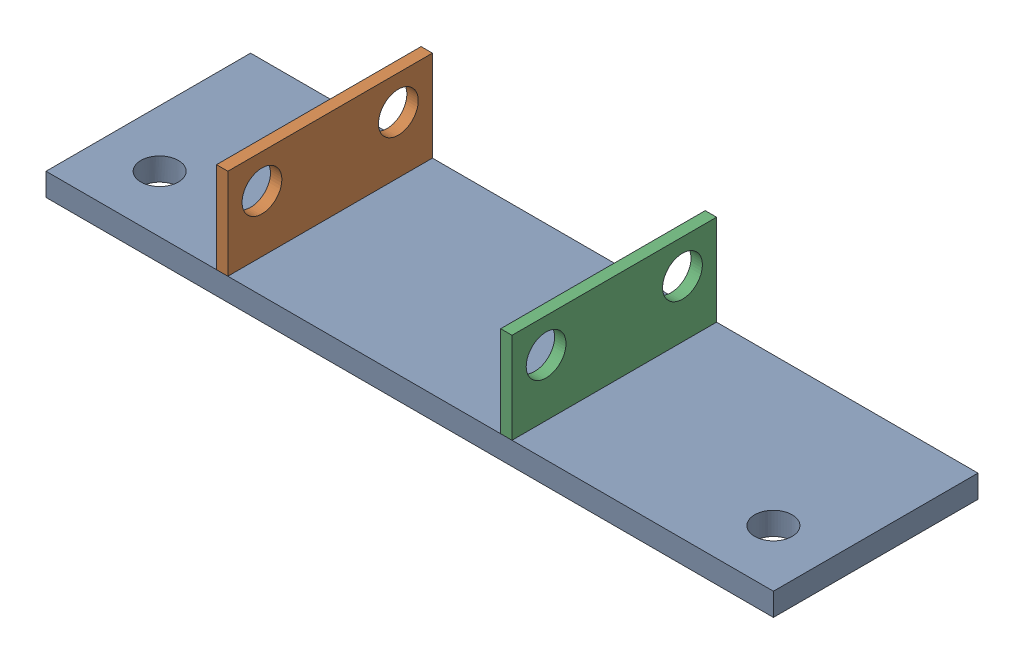
SolidWorks assembly Cam_Support_Ass_3, configuration Default. Lengths in mm.
Overall size (406.4 63.5 114.3).
3 component instances, 2 part files, 0 mates.
Components (placement in the parent):
- 01-020-00-0-1: 01-020-00-0 [Default] at (-198.1826 -10.9875 112.043) size (406.4 12.7 114.3)
- Cam Support Tab-1: Cam Support Tab [Default] at (-102.9326 1.7125 112.043) x (0 1 0) z (-1 0 0) size (50.8 114.3 6.35)
- Cam Support Tab-2: Cam Support Tab [Default] at (55.8174 1.7125 112.043) x (0 1 0) z (-1 0 0) size (50.8 114.3 6.35)
